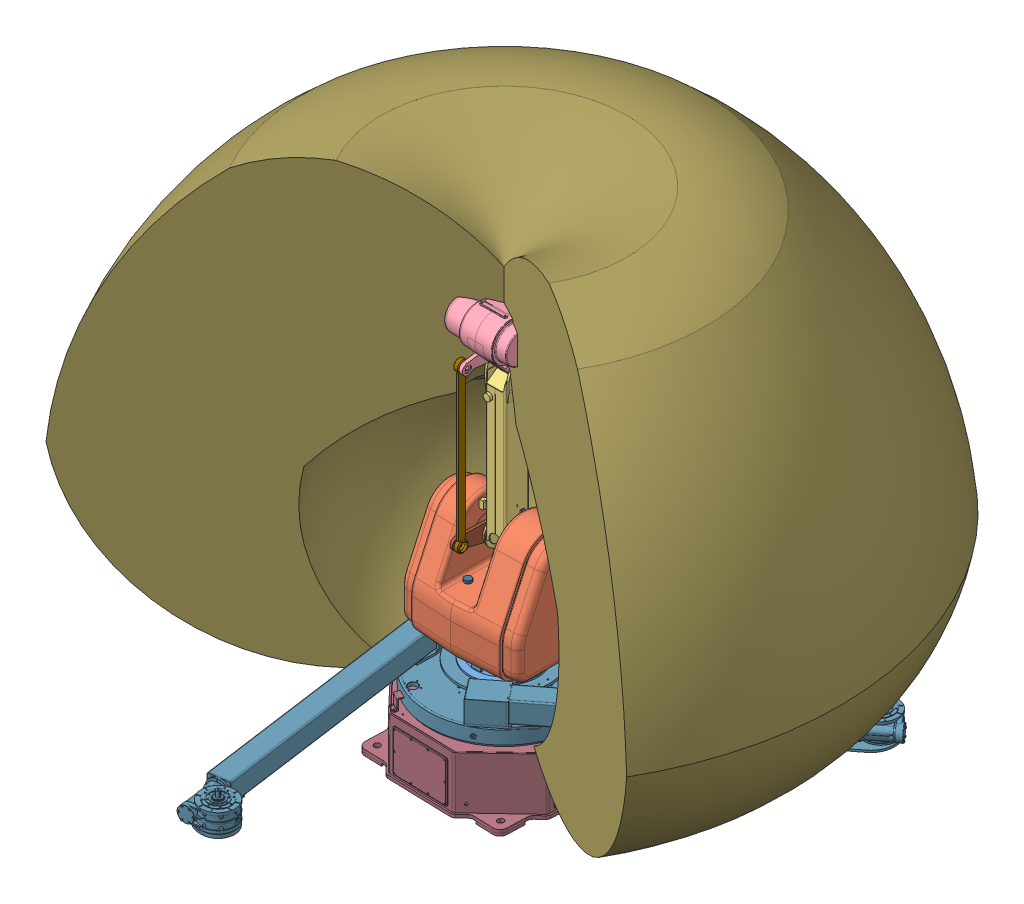
SolidWorks assembly EGR3ST 数模（带配合，SW2015版）, configuration 默认. Lengths in mm.
Overall size (3858.83 2956.6 3703.67).
14 component instances, 14 part files, 30 mates.
Components (placement in the parent):
- 复件 Group1^EGR3ST 数模（带配合，SW2015版）-1: 复件 Group1^EGR3ST 数模（带配合，SW2015版） [默认] at origin size (390 170 390) (virtual)
- 复件 Group2^EGR3ST 数模（带配合，SW2015版）-1: 复件 Group2^EGR3ST 数模（带配合，SW2015版） [默认] at origin size (675 769.5 617.78) (virtual)
- 复件 Group3^EGR3ST 数模（带配合，SW2015版）-1: 复件 Group3^EGR3ST 数模（带配合，SW2015版） [默认] at origin size (184 1010 155) (virtual)
- 复件 Group6^EGR3ST 数模（带配合，SW2015版）-1: 复件 Group6^EGR3ST 数模（带配合，SW2015版） [默认] at (-1 0.0357 -10.9599) x (1 0 0) z (0 -0.006508 0.999979) size (365.01 350.94 1383.44) (virtual)
- 复件 Group7^EGR3ST 数模（带配合，SW2015版）-1: 复件 Group7^EGR3ST 数模（带配合，SW2015版） [默认] at (0 0.0357 -10.9599) x (1 0 0) z (0 -0.006508 0.999979) size (120.77 126.01 105.71) (virtual)
- 复件 Group8^EGR3ST 数模（带配合，SW2015版）-1: 复件 Group8^EGR3ST 数模（带配合，SW2015版） [默认] at (0 0.0357 -10.9599) x (1 0 0) z (0 -0.006508 0.999979) size (76 106.45 106.26) (virtual)
- 复件 3075 Perno-1^EGR3ST 数模（带配合，SW2015版）-1: 复件 3075 Perno-1^EGR3ST 数模（带配合，SW2015版） [默认] at (0 0.0357 -10.9599) x (1 0 0) z (0 -0.006508 0.999979) size (42 42.04 59.61) (virtual)
- 复件 5401 tacca di zero-1^EGR3ST 数模（带配合，SW2015版）-1: 复件 5401 tacca di zero-1^EGR3ST 数模（带配合，SW2015版） [默认] at (0 0.0357 -10.9599) x (1 0 0) z (0 -0.006508 0.999979) size (18 30.46 14.44) (virtual)
- 复件 8851 Tirante i=900-1^EGR3ST 数模（带配合，SW2015版）-1: 复件 8851 Tirante i=900-1^EGR3ST 数模（带配合，SW2015版） [默认] at (-1.35 -1.2899 0.1748) size (29.85 963 63) (virtual)
- 复件 Antivibrante LAGOS P4015-M8-1^EGR3ST 数模（带配合，SW2015版）-1: 复件 Antivibrante LAGOS P4015-M8-1^EGR3ST 数模（带配合，SW2015版） [默认] at (8.2914 0 3.5507) size (40 38 40) (virtual)
- 复件 小臂摇杆10551 Flangia fissaggio tirante-2^EGR3ST 数模（带配合，SW2015版）-1: 复件 小臂摇杆10551 Flangia fissaggio tirante-2^EGR3ST 数模（带配合，SW2015版） [默认] at (0 0.0166 -5.1025) x (1 0 0) z (0 -0.006508 0.999979) size (15 111 281.6) (virtual)
- 复件 GR30 3D 包络图^EGR3ST 数模（带配合，SW2015版）-1: 复件 GR30 3D 包络图^EGR3ST 数模（带配合，SW2015版） [默认] x (0 0 -1) z (1 0 0) size (3259.14 2956.6 3858.83) (virtual)
- EGR3G3-C20-01 底座部分-1: EGR3G3-C20-01 底座部分 [默认] at (0 -271 0) x (0.999587 0 0.028729) z (-0.028729 0 0.999587) size (950 462.06 950)
- EGR3G3-C20-02 单爪-1: EGR3G3-C20-02 单爪 [默认] at (0 -271 0) x (0.999595 0 0.028443) z (-0.028443 0 0.999595) size (3034.74 263 2688.88)
Mates (geometry in assembly coordinates):
- 同心1: concentric anti-aligned: cylinder of 复件 Group1^EGR3ST 数模（带配合，SW2015版）-1 through (0 0 0) axis (0 -1 0) radius 195; cylinder of 复件 Group2^EGR3ST 数模（带配合，SW2015版）-1 through (0 328 0) axis (0 1 0) radius 137.5
- 距离1: distance = 3 mm anti-aligned: plane of 复件 Group2^EGR3ST 数模（带配合，SW2015版）-1 through (0 201 0) normal (0 -1 0); plane of 复件 Group1^EGR3ST 数模（带配合，SW2015版）-1 through (0 198 0) normal (0 1 0)
- 同心2: concentric aligned: cylinder of 复件 Group2^EGR3ST 数模（带配合，SW2015版）-1 through (-300 784 0) axis (-1 0 0) radius 65; cylinder of 复件 Group3^EGR3ST 数模（带配合，SW2015版）-1 through (-63.5 784 0) axis (-1 0 0) radius 60
- 距离2: distance = 65 mm anti-aligned: plane of 复件 Group3^EGR3ST 数模（带配合，SW2015版）-1 through (-37.5 1624 -60) normal (-1 0 0); plane of 复件 Group2^EGR3ST 数模（带配合，SW2015版）-1 through (-102.5 959 -295.001) normal (1 0 0)
- 同心3: concentric anti-aligned: cylinder of 复件 8851 Tirante i=900-1^EGR3ST 数模（带配合，SW2015版）-1 through (-63.925 810.215 198.2745) axis (-1 0 0) radius 23.5; cylinder of 复件 小臂摇杆10551 Flangia fissaggio tirante-2^EGR3ST 数模（带配合，SW2015版）-1 through (-82 810.215 198.2745) axis (1 0 0) radius 10
- 距离3: distance = 3.15 mm anti-aligned: plane of 复件 8851 Tirante i=900-1^EGR3ST 数模（带配合，SW2015版）-1 through (-63.85 778.715 198.2745) normal (-1 0 0); plane of 复件 小臂摇杆10551 Flangia fissaggio tirante-2^EGR3ST 数模（带配合，SW2015版）-1 through (-67 784 0) normal (1 0 0)
- 同心4: concentric anti-aligned: cylinder of 复件 Group6^EGR3ST 数模（带配合，SW2015版）-1 through (-29 1710.215 198.2745) axis (1 0 0) radius 10; cylinder of 复件 8851 Tirante i=900-1^EGR3ST 数模（带配合，SW2015版）-1 through (-63.925 1710.215 198.2745) axis (-1 0 0) radius 31.5
- 距离4: distance = 5 mm anti-aligned: plane of 复件 Group6^EGR3ST 数模（带配合，SW2015版）-1 through (-29 1684 0) normal (-1 0 0); plane of 复件 8851 Tirante i=900-1^EGR3ST 数模（带配合，SW2015版）-1 through (-34 1733.715 198.2745) normal (1 0 0)
- 同心5: concentric anti-aligned: cylinder of 复件 Group3^EGR3ST 数模（带配合，SW2015版）-1 through (-99.0244 1684 0) axis (-1 0 0) radius 25; cylinder of 复件 Group6^EGR3ST 数模（带配合，SW2015版）-1 through (-29 1684 0) axis (1 0 0) radius 32.5
- 距离5: distance = 8.5 mm anti-aligned: plane of 复件 Group6^EGR3ST 数模（带配合，SW2015版）-1 through (-29 1684 0) normal (-1 0 0); plane of 复件 Group3^EGR3ST 数模（带配合，SW2015版）-1 through (-37.5 1624 10) normal (1 0 0)
- 同心6: concentric anti-aligned: cylinder of 复件 Group6^EGR3ST 数模（带配合，SW2015版）-1 through (168.5 1681.9289 -1099.6702) axis (-1 0 0) radius 54; cylinder of 复件 Group7^EGR3ST 数模（带配合，SW2015版）-1 through (67.45 1681.9289 -1099.6702) axis (1 0 0) radius 44
- 距离6: distance = 8.25 mm anti-aligned: plane of 复件 Group6^EGR3ST 数模（带配合，SW2015版）-1 through (60.5 1681.9289 -1099.6702) normal (-1 0 0); plane of 复件 Group7^EGR3ST 数模（带配合，SW2015版）-1 through (52.25 1637.9289 -1099.6702) normal (1 0 0)
- 同心7: concentric aligned: cylinder of 复件 Group7^EGR3ST 数模（带配合，SW2015版）-1 through (0 1609.8289 -1099.6702) axis (0 1 0) radius 40; cylinder of 复件 Group8^EGR3ST 数模（带配合，SW2015版）-1 through (0 1439.0888 -1099.6702) axis (0 1 0) radius 38
- 距离7: distance = 1 mm anti-aligned: plane of 复件 Group7^EGR3ST 数模（带配合，SW2015版）-1 through (-13.7766 1609.8289 -1132.9298) normal (0 -1 0); plane of 复件 Group8^EGR3ST 数模（带配合，SW2015版）-1 through (0 1608.8289 -1099.6702) normal (0 1 0)
- 同心8: concentric aligned: cylinder of 复件 Group8^EGR3ST 数模（带配合，SW2015版）-1 through (0 1568.8289 -1133.7702) axis (0 0 1) radius 22.5; cylinder of 复件 3075 Perno-1^EGR3ST 数模（带配合，SW2015版）-1 through (0 1568.8289 -1178.2702) axis (0 0 1) radius 21
- 距离8: distance = 1.5 mm anti-aligned: plane of 复件 Group8^EGR3ST 数模（带配合，SW2015版）-1 through (0 1589.8289 -1167.7702) normal (0 0 -1); plane of 复件 3075 Perno-1^EGR3ST 数模（带配合，SW2015版）-1 through (0 1547.8289 -1169.2702) normal (0 0 1)
- 同心9: concentric anti-aligned: cylinder of 复件 Group2^EGR3ST 数模（带配合，SW2015版）-1 through (-300 784 0) axis (-1 0 0) radius 65; cylinder of 复件 小臂摇杆10551 Flangia fissaggio tirante-2^EGR3ST 数模（带配合，SW2015版）-1 through (-82 784 0) axis (1 0 0) radius 32.5
- 同心10: concentric aligned: cylinder of 复件 Group7^EGR3ST 数模（带配合，SW2015版）-1 through (45.25 1699.6413 -1052.6779) axis (0 0.139173 0.990268) radius 1.25; cylinder of 复件 5401 tacca di zero-1^EGR3ST 数模（带配合，SW2015版）-1 through (45.25 1699.314 -1055.0074) axis (0 0.139173 0.990268) radius 1.75
- 同心11: concentric aligned: cylinder of 复件 Group7^EGR3ST 数模（带配合，SW2015版）-1 through (45.25 1677.8554 -1049.6161) axis (0 0.139173 0.990268) radius 1.25; cylinder of 复件 5401 tacca di zero-1^EGR3ST 数模（带配合，SW2015版）-1 through (45.25 1677.5281 -1051.9456) axis (0 0.139173 0.990268) radius 1.75
- 同心12: concentric anti-aligned: cylinder of 复件 Group7^EGR3ST 数模（带配合，SW2015版）-1 through (-167.2965 1681.9289 -1099.6702) axis (1 0 0) radius 49; cylinder of 复件 5401 tacca di zero-1^EGR3ST 数模（带配合，SW2015版）-1 through (48.25 1681.9289 -1099.6702) axis (-1 0 0) radius 49
- 重合9: coincident aligned: plane of 复件 Group1^EGR3ST 数模（带配合，SW2015版）-1 through (-0.5 231.5 135) normal (1 0 0); plane of 复件 Group2^EGR3ST 数模（带配合，SW2015版）-1 through (-0.5 241 113) normal (1 0 0)
- 重合10: coincident aligned: plane of 复件 Group2^EGR3ST 数模（带配合，SW2015版）-1 through (95.5 970.5 -0.5) normal (0 0 1); plane of 复件 Group3^EGR3ST 数模（带配合，SW2015版）-1 through (66.5 980 -0.5) normal (0 0 1)
- 平行1: parallel aligned: plane of 复件 Group3^EGR3ST 数模（带配合，SW2015版）-1 through (-63.501 1704.1593 36.8491) normal (0 -0.882948 0.469472); plane of 复件 Group6^EGR3ST 数模（带配合，SW2015版）-1 through (79 1704.4911 38.0277) normal (0 -0.882948 0.469472)
- 重合12: coincident aligned: plane of 复件 Group6^EGR3ST 数模（带配合，SW2015版）-1 through (60.5 1689.7842 -1040.1845) normal (0 0.990268 -0.139173); plane of 复件 5401 tacca di zero-1^EGR3ST 数模（带配合，SW2015版）-1 through (42.25 1689.5058 -1042.165) normal (0 0.990268 -0.139173)
- 重合13: coincident aligned: plane of 复件 Group7^EGR3ST 数模（带配合，SW2015版）-1 through (0.5 1614.8289 -1059.6702) normal (-1 0 0); plane of 复件 Group8^EGR3ST 数模（带配合，SW2015版）-1 through (0.5 1603.8289 -1061.6702) normal (-1 0 0)
- 重合14: coincident aligned: plane of 复件 Group8^EGR3ST 数模（带配合，SW2015版）-1 through (0.5 1589.3289 -1162.7702) normal (-1 0 0); plane of 复件 3075 Perno-1^EGR3ST 数模（带配合，SW2015版）-1 through (0.5 1589.8289 -1118.7702) normal (-1 0 0)
- 同心13: concentric anti-aligned: cylinder of 复件 Group1^EGR3ST 数模（带配合，SW2015版）-1 through (0 0 0) axis (0 -1 0) radius 195; cylinder of EGR3G3-C20-02 单爪-1 through (0 178 0) axis (0 1 0) radius 135
- 重合15: coincident anti-aligned: plane of 复件 Group1^EGR3ST 数模（带配合，SW2015版）-1 through (0 178 0) normal (0 -1 0); plane of EGR3G3-C20-02 单爪-1 through (7.3951 178 -259.8948) normal (0 1 0)
- 同心14: concentric anti-aligned: cylinder of EGR3G3-C20-01 底座部分-1 through (0 27 0) axis (0 -1 0) radius 165; cylinder of EGR3G3-C20-02 单爪-1 through (0 178 0) axis (0 1 0) radius 135
- 重合16: coincident anti-aligned: plane of EGR3G3-C20-01 底座部分-1 through (118.1585 158 -111.5563) normal (0 1 0); plane of EGR3G3-C20-02 单爪-1 through (4.6219 158 -162.4343) normal (0 -1 0)
